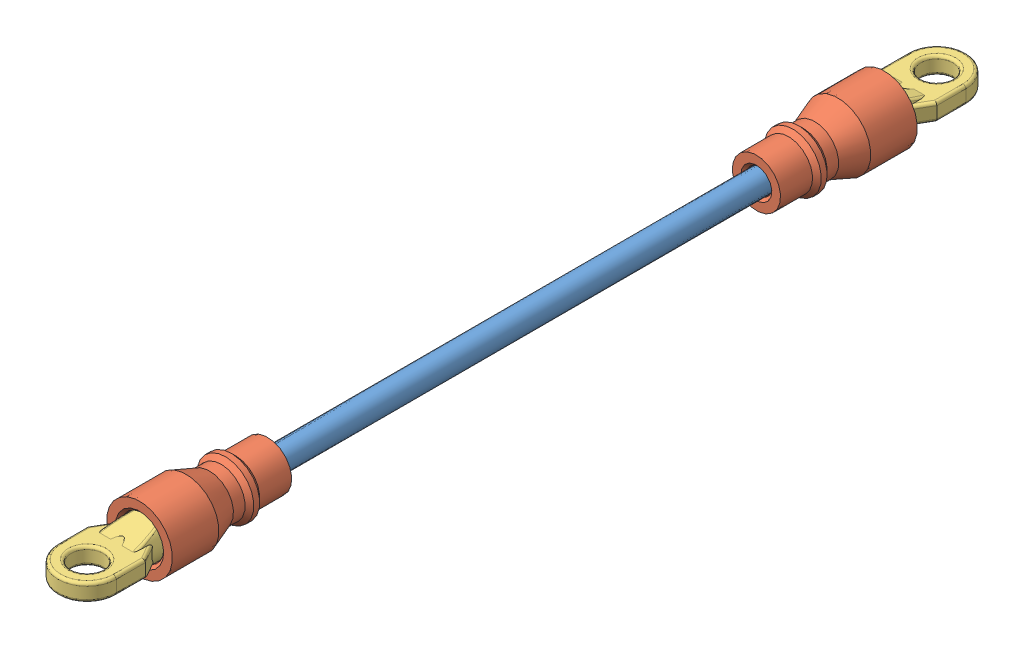
SolidWorks assembly Rod Assembly, configuration Default. Lengths in mm.
Overall size (14.77 14.77 156).
5 component instances, 3 part files, 10 mates.
Components (placement in the parent):
- Carbon Rod-1: Carbon Rod [Default] at origin size (4 4 104)
- Bearing Shaft Coupler-1: Bearing Shaft Coupler [Default] at (0 0 -12) x (-0.995836 -0.091164 0) z (0 0 1) size (11.3 11.3 22)
- Bearing Shaft Coupler-2: Bearing Shaft Coupler [Default] at (0 0 116) x (-0.923728 -0.383049 0) z (0 0 -1) size (11.3 11.3 22)
- Rod Ends-1: Rod Ends [Default] at (0 0 108) size (10 7 22)
- Rod Ends-2: Rod Ends [Default] at (0 0 -4) x (-1 0 0) z (0 0 -1) size (10 7 22)
Mates (geometry in assembly coordinates):
- Concentric1: concentric aligned: cylinder of Carbon Rod-1 through (0 0 104) axis (0 0 -1) radius 2; cylinder of Bearing Shaft Coupler-1 through (0 0 10) axis (0 0 -1) radius 2.15
- Coincident1: coincident anti-aligned: plane of Carbon Rod-1 through (0 0 0) normal (0 0 -1); plane of Bearing Shaft Coupler-1 through (0 0 0) normal (0 0 1)
- Coincident2: coincident anti-aligned: plane of Carbon Rod-1 through (0 0 104) normal (0 0 1); plane of Bearing Shaft Coupler-2 through (0 0 104) normal (0 0 -1)
- Concentric2: concentric anti-aligned: cylinder of Carbon Rod-1 through (0 0 104) axis (0 0 -1) radius 2; cylinder of Bearing Shaft Coupler-2 through (0 0 94) axis (0 0 1) radius 2.15
- Coincident3: coincident anti-aligned: circle of Bearing Shaft Coupler-2; plane of Rod Ends-1 through (0 0 108) normal (0 0 -1)
- Concentric3: concentric anti-aligned: cylinder of Bearing Shaft Coupler-2 through (0 0 108) axis (0 0 1) radius 3.65; cylinder of Rod Ends-1 through (0 0 120) axis (0 0 -1) radius 3.5
- Coincident4: coincident anti-aligned: circle of Bearing Shaft Coupler-1; plane of Rod Ends-2 through (0 0 -4) normal (0 0 1)
- Concentric4: concentric anti-aligned: cylinder of Bearing Shaft Coupler-1 through (0 0 -4) axis (0 0 -1) radius 3.65; cylinder of Rod Ends-2 through (0 0 -16) axis (0 0 1) radius 3.5
- Coincident5: coincident aligned: plane of Rod Ends-1 through (0 0 108) normal (0 1 0); plane of assembly
- Coincident6: coincident aligned: plane of Rod Ends-2; plane of assembly
